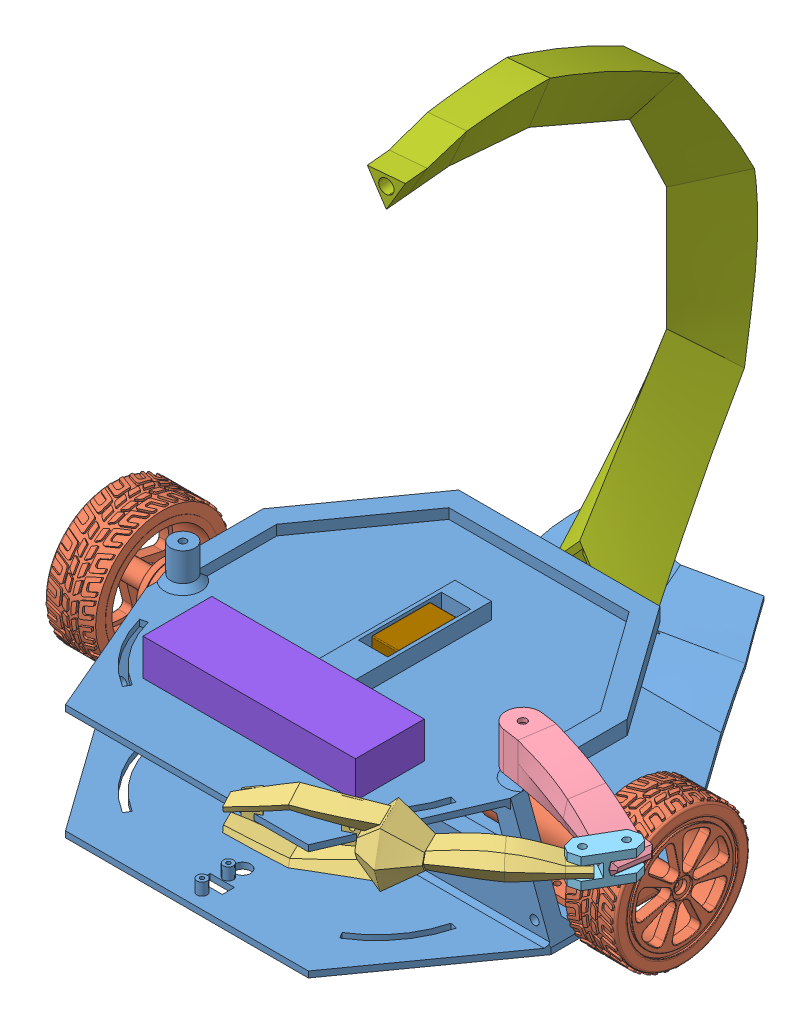
SolidWorks assembly Total, configuration Default. Lengths in mm.
Overall size (296.45 277.15 361.29).
12 component instances, 9 part files, 21 mates.
Components (placement in the parent):
- Base-1: Base [Default] at (-81.0935 -52.508 57.0644) size (220 74 248.08)
- Ass_Motor-1: Ass_Motor [Default] at (-55.0796 -39.1391 147.507) x (0 0 1) z (1 0 0) size (68.01 68.01 88)
- Ass_Motor-2: Ass_Motor [Default] at (-107.1074 -39.1391 -33.3781) x (0 0 -1) z (-1 0 0) size (68.01 68.01 88)
- garra-1: garra [Default] at (-8.2404 6.4275 147.2087) x (0.440439 0 0.897783) z (0.897783 0 -0.440439) size (32.5 29.53 133.95)
- patinha-1: patinha [Default] at (2.9065 28.492 79.0644) x (-0.989225 0 -0.146402) z (-0.146402 0 0.989225) size (76.7 24.06 19.92)
- união-1: união [Default] at (59.4469 3.9312 112.1923) x (0.502142 0 -0.864785) z (-0.864785 0 -0.502142) size (28 14.5 12)
- Long Range SHARP IR Sensors - #GP2Y0A21YK0F-1: Long Range SHARP IR Sensors - #GP2Y0A21YK0F [Default] at (-95.8877 -23.508 84.7644) size (44.5 18.9 13.5)
- Long Range SHARP IR Sensors - #GP2Y0A21YK0F-2: Long Range SHARP IR Sensors - #GP2Y0A21YK0F [Default] at (-151.0825 -23.508 118.4929) x (0.766044 0 -0.642788) z (0.642788 0 0.766044) size (44.5 18.9 13.5)
- Long Range SHARP IR Sensors - #GP2Y0A21YK0F-3: Long Range SHARP IR Sensors - #GP2Y0A21YK0F [Default] at (-33.856 -23.508 99.4021) x (0.766044 0 0.642788) z (-0.642788 0 0.766044) size (44.5 18.9 13.5)
- cauda-1: cauda [Default] at (-81.6343 -22.3235 51.0889) x (-0.090141 0 -0.995929) z (0.995929 0 -0.090141) size (259.78 264.15 51.96)
- bateria-1: bateria [Default] at (-28.2665 22.492 130.5884) x (0 0 -1) z (-1 0 0) size (34 18 105)
- Servo S05NF-1: Servo S05NF [Default] at (-81.0935 11.692 48.6844) x (0 0 1) z (1 0 0) size (39.75 35.2 13.5)
Mates (geometry in assembly coordinates):
- Coincident2: coincident anti-aligned: plane of Base-1 through (-81.0935 -49.508 57.0644) normal (0 1 0); plane of Ass_Motor-1 through (-1.0935 -49.508 44.0644) normal (0 -1 0)
- Coincident3: coincident anti-aligned: plane of Base-1 through (-81.0935 -49.508 57.0644) normal (0 1 0); plane of Ass_Motor-2 through (-161.0935 -49.508 70.0644) normal (0 -1 0)
- Distance1: distance = 17 mm aligned: plane of Ass_Motor-2 through (-161.0935 -46.508 70.0644) normal (0 0 1); plane of Base-1 through (-191.0935 -49.508 87.0644) normal (0 0 1)
- Concentric2: concentric anti-aligned: cylinder of Ass_Motor-1 through (31.9065 -25.508 57.0644) axis (-1 0 0) radius 12.5; cylinder of Ass_Motor-2 through (-194.0935 -25.508 57.0644) axis (1 0 0) radius 12.5
- Distance2: distance = 30 mm anti-aligned: plane of Ass_Motor-1 through (-1.0935 -49.508 44.0644) normal (-1 0 0); plane of Base-1 through (28.9065 -49.508 27.0644) normal (1 0 0)
- Distance3: distance = 30 mm anti-aligned: plane of Ass_Motor-2 through (-161.0935 -49.508 70.0644) normal (1 0 0); plane of Base-1 through (-191.0935 -49.508 27.0644) normal (-1 0 0)
- Concentric4: concentric anti-aligned: cylinder of patinha-1 through (65.3053 14.4312 90.1541) axis (0 -1 0) radius 1.75; cylinder of união-1 through (65.3053 -0.0688 90.1541) axis (0 1 0) radius 1.75
- Coincident8: coincident anti-aligned: plane of patinha-1 through (71.5725 10.4312 81.9593) normal (0 1 0); plane of união-1 through (63.1294 10.4312 81.9526) normal (0 -1 0)
- Coincident9: coincident anti-aligned: plane of garra-1 through (63.3784 3.9312 104.3303) normal (0 -1 0); plane of união-1 through (49.0694 3.9312 106.1666) normal (0 1 0)
- Concentric5: concentric aligned: cylinder of garra-1 through (57.271 0.0015 103.9907) axis (0 1 0) radius 1.75; cylinder of união-1 through (57.271 -0.0688 103.9907) axis (0 1 0) radius 1.75
- Coincident10: coincident anti-aligned: plane of Base-1 through (-81.0935 -52.508 91.0644) normal (0 0 1); plane of Long Range SHARP IR Sensors - #GP2Y0A21YK0F-1 through (-62.6377 -17.2348 91.0644) normal (0 0 -1)
- Coincident13: coincident aligned: plane of Long Range SHARP IR Sensors - #GP2Y0A21YK0F-1 through (-95.8877 -23.508 84.7644) normal (0 -1 0); plane of Long Range SHARP IR Sensors - #GP2Y0A21YK0F-2 through (-151.0825 -23.508 118.4929) normal (0 -1 0)
- Coincident15: coincident aligned: plane of Long Range SHARP IR Sensors - #GP2Y0A21YK0F-1 through (-95.8877 -23.508 84.7644) normal (0 -1 0); plane of Long Range SHARP IR Sensors - #GP2Y0A21YK0F-3 through (-33.856 -23.508 99.4021) normal (0 -1 0)
- Coincident16: coincident anti-aligned: plane of Base-1 through (-81.0935 -46.508 57.0644) normal (0 1 0); plane of cauda-1 through (-75.4382 -46.508 119.5477) normal (0 -1 0)
- Concentric6: concentric aligned: cylinder of Base-1 through (-81.0935 -46.508 57.0644) axis (0 -1 0) radius 9.2514; cylinder of cauda-1 through (-81.0935 -9.508 57.0644) axis (0 -1 0) radius 1.75
- Concentric7: concentric anti-aligned: cylinder of Base-1 through (2.9065 9.492 79.0644) axis (0 -1 0) radius 6; cylinder of patinha-1 through (2.9065 11.492 79.0644) axis (0 1 0) radius 6.35
- Distance4: distance = 25 mm aligned: plane of Long Range SHARP IR Sensors - #GP2Y0A21YK0F-1 through (-95.8877 -23.508 84.7644) normal (0 -1 0); plane of Base-1 through (-81.0935 1.492 57.0644) normal (0 -1 0)
- Coincident21: coincident anti-aligned: plane of Base-1 through (2.9065 9.492 79.0644) normal (0 1 0); plane of patinha-1 through (2.9065 9.492 79.0644) normal (0 -1 0)
- Coincident22: coincident anti-aligned: plane of Base-1 through (-81.0935 4.492 57.0644) normal (0 1 0); plane of bateria-1 through (-133.2665 4.492 130.5884) normal (0 -1 0)
- Coincident32: coincident anti-aligned: plane of Base-1 through (-81.0935 -10.308 57.0644) normal (0 1 0); plane of Servo S05NF-1 through (-85.8435 -10.308 66.5594) normal (0 -1 0)
- Concentric11: concentric aligned: cylinder of cauda-1 through (-81.0935 -25.508 57.0644) axis (0 -1 0) radius 12.5; cylinder of Servo S05NF-1 through (-81.0935 -16.0624 57.0644) axis (0 -1 0) radius 0.9
